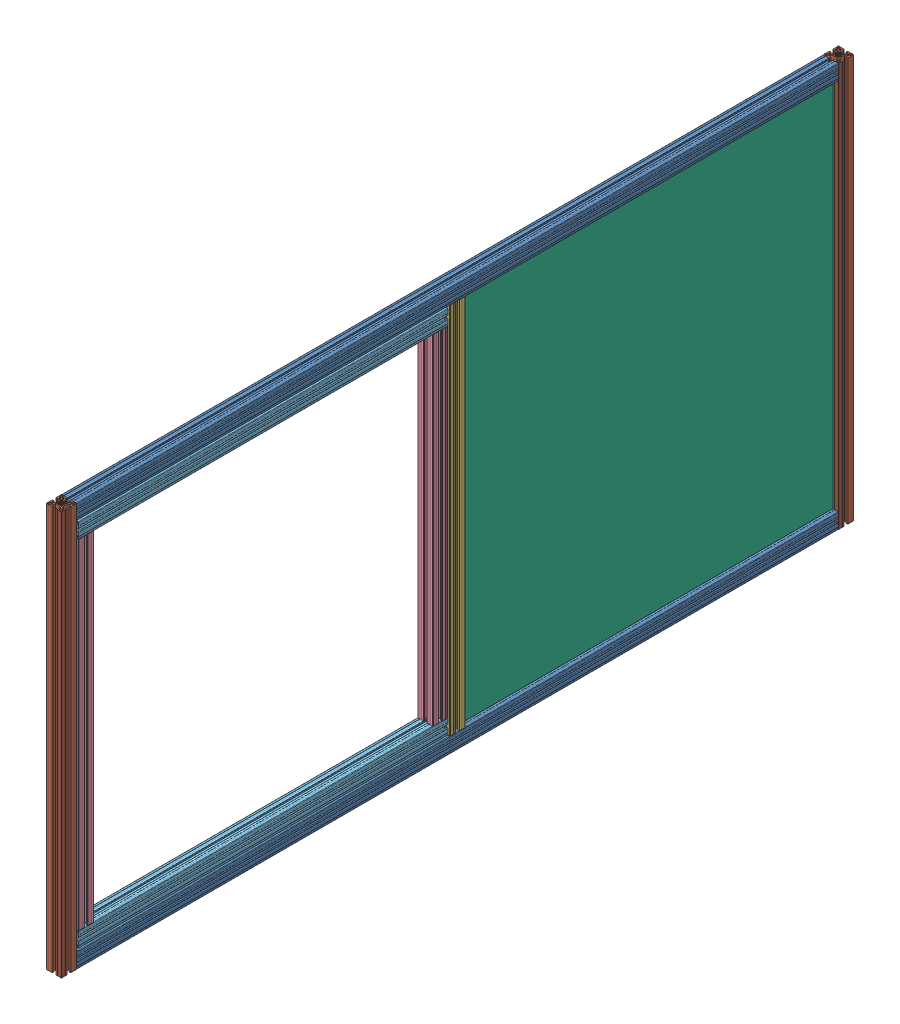
SolidWorks assembly Lateral_C_Porta_Mod2, configuration Valor predeterminado. Lengths in mm.
Overall size (40 1060 2080).
11 component instances, 6 part files, 9 mates.
Components (placement in the parent):
- Perfil_Alum_4x4x200-1: Perfil_Alum_4x4x200 [Valor predeterminado] at (-42.2544 -2.229 2000) size (40 40 2000)
- Perfil_Alum_4x4x106-1: Perfil_Alum_4x4x106 [Valor predeterminado] at (-42.2544 507.771 3020) x (1 0 0) z (0 -1 0) size (40 40 1060)
- Perfil_Alum_4x4x98-1: Perfil_Alum_4x4x98 [Valor predeterminado] at (-42.2544 507.771 2000) x (1 0 0) z (0 -1 0) size (40 40 980)
- Perfil_Alum_4x4x106-2: Perfil_Alum_4x4x106 [Valor predeterminado] at (-42.2544 507.771 980) x (1 0 0) z (0 -1 0) size (40 40 1060)
- Perfil_Alum_4x4x200-2: Perfil_Alum_4x4x200 [Valor predeterminado] at (-42.2544 1017.771 2000) size (40 40 2000)
- Porta_Mod_Clean-1: Porta_Mod_Clean [Valor predeterminado] at (-25.965 113.1173 1603.2592) size (40 970 970)
  - Perfil_Alum_4x4x89-1: Perfil_Alum_4x4x89 [Valor predeterminado] at (-16.2893 394.6537 1371.7408) x (1 0 0) z (0 -1 0) size (40 40 890)
  - Perfil_Alum_4x4x97-1: Perfil_Alum_4x4x97 [Valor predeterminado] at (-16.2893 -70.3463 906.7408) size (40 40 970)
  - Perfil_Alum_4x4x97-2: Perfil_Alum_4x4x97 [Valor predeterminado] at (-16.2893 859.6537 906.7408) size (40 40 970)
  - Perfil_Alum_4x4x89-2: Perfil_Alum_4x4x89 [Valor predeterminado] at (-16.2893 394.6537 441.7408) x (1 0 0) z (0 -1 0) size (40 40 890)
- Policarbonato 1x1-1: Policarbonato 1x1 [Valor predeterminado] at (-42.2544 507.771 1490) x (0 0 -1) z (1 0 0) size (1000 1000 6)
Mates (geometry in assembly coordinates):
- Coincidente1: coincident: point of Perfil_Alum_4x4x200-1; unknown of Perfil_Alum_4x4x106-1
- Coincidente2: coincident: unknown of Perfil_Alum_4x4x200-1; unknown of Perfil_Alum_4x4x106-1
- Distância1: distance = 980 mm anti-aligned: plane of Perfil_Alum_4x4x98-1 through (-27.8544 17.771 2020) normal (0 0 1); plane of Perfil_Alum_4x4x106-1 through (-23.7544 -22.229 3000) normal (0 0 -1)
- Coincidente8: coincident: point of assembly; point of assembly; moEndPointRef_w of Perfil_Alum_4x4x200-1; moEndPointRef_w of Perfil_Alum_4x4x106-2
- Coincidente9: coincident: unknown of Perfil_Alum_4x4x200-1; unknown of Perfil_Alum_4x4x106-2
- Coincidente10: coincident: unknown of Perfil_Alum_4x4x106-1; unknown of Perfil_Alum_4x4x200-2
- Coincidente11: coincident anti-aligned: plane of Perfil_Alum_4x4x98-1 through (-37.1539 17.771 1990) normal (0 0 -1); plane of Policarbonato 1x1-1 through (-39.2544 1007.771 1990) normal (0 0 1)
- Coincidente12: coincident: plane of Perfil_Alum_4x4x200-2 through (-37.1539 1007.771 3000) normal (0 -1 0); plane of Policarbonato 1x1-1 through (-39.2544 1007.771 1990) normal (0 1 0)
- Distância7: distance = 1.15 mm anti-aligned: plane of Perfil_Alum_4x4x106-2 through (-38.1044 -22.229 995.9) normal (-1 0 0); plane of Policarbonato 1x1-1 through (-39.2544 507.771 1490) normal (1 0 0)
